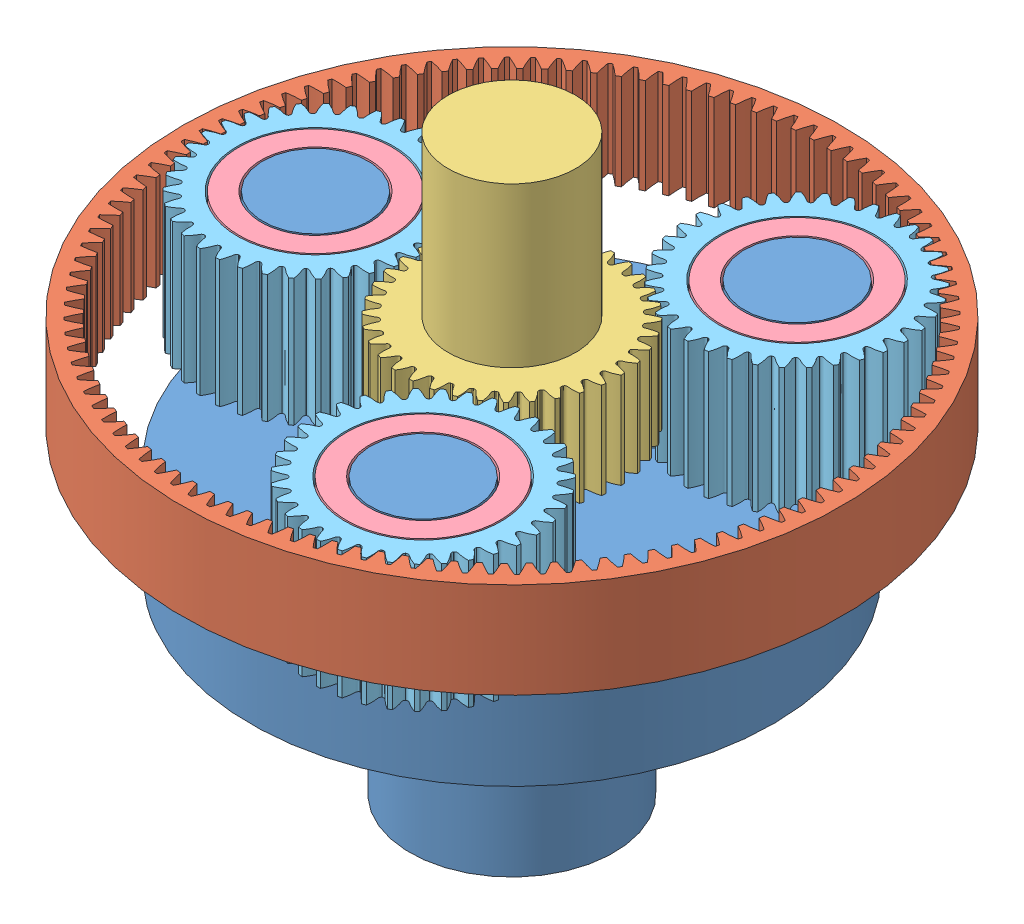
SolidWorks assembly Planetary_Gearbox, configuration 默认. Lengths in mm.
Overall size (143.01 90 143.01).
9 component instances, 5 part files, 28 mates.
Components (placement in the parent):
- Carrier-1: Carrier [默认] at (-29.6302 -12.6196 -10.1816) x (0.841499 0 0.540258) z (-0.540258 0 0.841499) size (82 65 82)
- RingGear-1: RingGear [默认] at (-29.6302 22.3804 -10.1816) x (-0.841499 0 -0.540258) z (0 -1 0) size (103.5 103.5 15)
- SunGear-1: SunGear [默认] at (-29.6302 7.3804 -10.1816) x (-0.790656 0 0.612261) z (0 1 0) size (33.22 33.22 40)
- Planet_bearing-5: Planet_bearing [默认] at (-61.9942 7.3804 -11.7085) size (24 15 24.5)
- Planet_bearing-6: Planet_bearing [默认] at (-12.1259 7.3804 -37.4462) x (0.965751 0 -0.259472) z (0.259472 0 0.965751) size (24 15 24.5)
- Planet_bearing-8: Planet_bearing [默认] at (-14.7706 7.3804 18.6099) x (0.998961 0 -0.045574) z (0.045574 0 0.998961) size (24 15 24.5)
- PlanetGear-5: PlanetGear [默认] at (-61.9942 2.3804 -11.7085) x (-0.754864 0 0.655881) z (0 1 0) size (33.81 33.78 20)
- PlanetGear-6: PlanetGear [默认] at (-12.1259 2.3804 -37.4462) x (0.841499 0 0.540258) z (0 1 0) size (33.81 33.78 20)
- PlanetGear-8: PlanetGear [默认] at (-14.7706 2.3804 18.6099) x (0.602003 0 -0.798494) z (0 1 0) size (33.81 33.78 20)
Mates (geometry in assembly coordinates):
- 同心8: concentric anti-aligned: cylinder of Carrier-1 through (-29.6302 2.3804 -10.1816) axis (0 -1 0) radius 41; cylinder of RingGear-1 through (-29.6302 7.3804 -10.1816) axis (0 1 0) radius 51.75
- 同心9: concentric aligned: cylinder of Carrier-1 through (-29.6302 2.3804 -10.1816) axis (0 -1 0) radius 41; cylinder of SunGear-1 through (-29.6302 47.3804 -10.1816) axis (0 -1 0) radius 10
- 重合1: coincident aligned: plane of Carrier-1 through (-12.1259 22.3804 -37.4462) normal (0 1 0); plane of RingGear-1 through (-29.6302 22.3804 -10.1816) normal (0 1 0)
- 重合2: coincident aligned: plane of RingGear-1 through (-29.6302 22.3804 -10.1816) normal (0 1 0); plane of SunGear-1 through (-29.6302 22.3804 -10.1816) normal (0 1 0)
- 同心10: concentric aligned: cylinder of Carrier-1 through (-61.9942 22.3804 -11.7085) axis (0 -1 0) radius 8.25; cylinder of Planet_bearing-5 through (-61.9942 22.3804 -11.7085) axis (0 -1 0) radius 12
- 重合3: coincident aligned: plane of Carrier-1 through (-61.9942 22.3804 -11.7085) normal (0 1 0); plane of Planet_bearing-5 through (-61.9942 22.3804 -11.7085) normal (0 1 0)
- 同心11: concentric aligned: cylinder of Carrier-1 through (-12.1259 22.3804 -37.4462) axis (0 -1 0) radius 8.25; cylinder of Planet_bearing-6 through (-12.1259 22.3804 -37.4462) axis (0 -1 0) radius 12
- 重合4: coincident aligned: plane of Carrier-1 through (-12.1259 22.3804 -37.4462) normal (0 1 0); plane of Planet_bearing-6 through (-12.1259 22.3804 -37.4462) normal (0 1 0)
- 同心12: concentric aligned: cylinder of Carrier-1 through (-14.7706 22.3804 18.6099) axis (0 -1 0) radius 8.25; cylinder of Planet_bearing-8 through (-14.7706 22.3804 18.6099) axis (0 -1 0) radius 12
- 重合5: coincident aligned: plane of Carrier-1 through (-14.7706 22.3804 18.6099) normal (0 1 0); plane of Planet_bearing-8 through (-14.7706 22.3804 18.6099) normal (0 1 0)
- 同心15: concentric anti-aligned: cylinder of Planet_bearing-5 through (-61.9942 22.3804 -11.7085) axis (0 -1 0) radius 12; cylinder of PlanetGear-5 through (-61.9942 2.3794 -11.7085) axis (0 1 0) radius 12.25
- 重合6: coincident aligned: plane of Carrier-1 through (-61.9942 22.3804 -11.7085) normal (0 1 0); plane of PlanetGear-5 through (-61.9942 22.3804 -11.7085) normal (0 1 0)
- 同心16: concentric anti-aligned: cylinder of Planet_bearing-6 through (-12.1259 22.3804 -37.4462) axis (0 -1 0) radius 12; cylinder of PlanetGear-6 through (-12.1259 2.3794 -37.4462) axis (0 1 0) radius 12.25
- 重合7: coincident aligned: plane of Carrier-1 through (-12.1259 22.3804 -37.4462) normal (0 1 0); plane of PlanetGear-6 through (-12.1259 22.3804 -37.4462) normal (0 1 0)
- 同心17: concentric anti-aligned: cylinder of Planet_bearing-8 through (-14.7706 22.3804 18.6099) axis (0 -1 0) radius 12; cylinder of PlanetGear-8 through (-14.7706 2.3794 18.6099) axis (0 1 0) radius 12.25
- 重合8: coincident aligned: plane of Carrier-1 through (-14.7706 22.3804 18.6099) normal (0 1 0); plane of PlanetGear-8 through (-14.7706 22.3804 18.6099) normal (0 1 0)
- 重合9: coincident anti-aligned: line of SunGear-1 through (-17.578 22.3804 -21.6692) axis (-0.723861 0 0.689945); line of PlanetGear-5 through (-16.9591 22.3804 -22.2591) axis (0.723861 0 -0.689945)
- 齿轮配合1: gear = 36 : 35 mm: circle of PlanetGear-5; circle of SunGear-1
- 重合11: coincident anti-aligned: line of SunGear-1 through (-29.8454 22.3804 6.467) axis (0.012923 0 -0.999916); line of PlanetGear-8 through (-29.8565 22.3804 7.322) axis (-0.012923 0 0.999916)
- 齿轮配合3: gear = 36 : 35 mm: circle of PlanetGear-8; circle of SunGear-1
- 重合12: coincident anti-aligned: line of SunGear-1 through (-21.2003 22.7399 2.0461) axis (-0.498938 0 0.866638); line of PlanetGear-6 through (-20.9234 22.7399 1.5651) axis (0.498938 0 -0.866638)
- 齿轮配合4: gear = 36 : 35 mm: circle of PlanetGear-6; circle of SunGear-1
- 重合13: coincident anti-aligned: line of RingGear-1 through (-29.6302 22.3804 -10.1816) axis (0.540258 0 -0.841499); line of PlanetGear-6 through (-4.0787 22.3804 -49.9803) axis (-0.540258 0 0.841499)
- 齿轮配合5: gear = 35 : 108 mm: circle of RingGear-1; circle of PlanetGear-6
- 重合20: coincident anti-aligned: line of RingGear-1 through (-29.6302 22.3804 -10.1816) axis (0.540258 0 -0.841499); line of PlanetGear-5 through (-4.2408 22.3804 -49.7278) axis (-0.540258 0 0.841499)
- 齿轮配合6: gear = 35 : 108 mm: circle of RingGear-1; circle of PlanetGear-5
- 重合21: coincident anti-aligned: line of RingGear-1 through (-29.6302 22.3804 -10.1816) axis (0.540258 0 -0.841499); line of PlanetGear-8 through (-4.2408 22.3804 -49.7278) axis (-0.540258 0 0.841499)
- 齿轮配合7: gear = 35 : 108 mm: circle of RingGear-1; circle of PlanetGear-8
